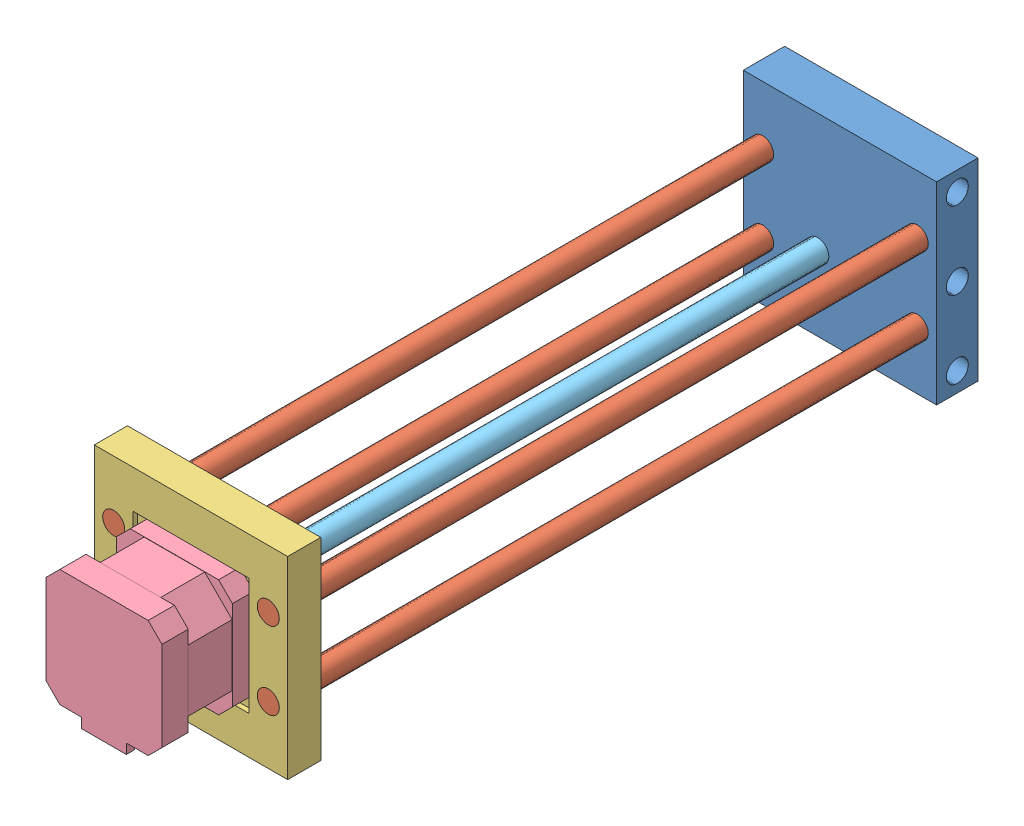
SolidWorks assembly Ensamblaje_Link2.2, configuration Predeterminado. Lengths in mm.
Overall size (70 70 281.5).
8 component instances, 5 part files, 19 mates.
Components (placement in the parent):
- Pieza3-1: Pieza3 [Predeterminado] x (-1 0 0) z (0 1 0) size (70 15 70)
- Pieza2-1: Pieza2 [Predeterminado] at (28 -14 0) x (0 0 1) z (-1 0 0) size (250 8 8)
- Pieza2-2: Pieza2 [Predeterminado] at (28 14 0) x (0 0 1) z (-1 0 0) size (250 8 8)
- Pieza2-3: Pieza2 [Predeterminado] at (-28 14 0) x (0 0 1) z (-1 0 0) size (250 8 8)
- Pieza2-4: Pieza2 [Predeterminado] at (-28 -14 0) x (0 0 1) z (-1 0 0) size (250 8 8)
- Pieza4-1: Pieza4 [Predeterminado] at (0 0 238) x (0 1 0) z (1 0 0) size (70 12 70)
- Motor Paso a Paso-1: Motor Paso a Paso [Predeterminado] at (0 0 281.5) x (-1 0 0) z (0 -1 0) size (42 55.2 46)
- Pieza6-1: Pieza6 [Predeterminado] at (0 0 23) x (1 0 0) z (0 -1 0) size (8 215 8)
Mates (geometry in assembly coordinates):
- Coincidente1: coincident aligned: plane of Pieza3-1 through (0 0 0) normal (0 0 1)
- Coincidente2: coincident aligned: plane of Pieza3-1 through (0 0 0) normal (0 1 0)
- Coincidente3: coincident anti-aligned: plane of Pieza3-1 through (0 0 0) normal (-1 0 0)
- Concéntrica1: concentric anti-aligned: cylinder of Pieza3-1 through (-28 -14 0) axis (0 0 1) radius 4; cylinder of Pieza2-4 through (-28 -14 250) axis (0 0 -1) radius 4
- Coincidente4: coincident aligned: plane of Pieza3-1 through (0 0 0) normal (0 0 -1); plane of Pieza2-4 through (-28 -14 0) normal (0 0 -1)
- Concéntrica2: concentric anti-aligned: cylinder of Pieza3-1 through (-28 14 0) axis (0 0 1) radius 4; cylinder of Pieza2-3 through (-28 14 250) axis (0 0 -1) radius 4
- Coincidente5: coincident aligned: plane of Pieza3-1 through (0 0 0) normal (0 0 -1); plane of Pieza2-3 through (-28 14 0) normal (0 0 -1)
- Concéntrica3: concentric anti-aligned: cylinder of Pieza3-1 through (28 14 0) axis (0 0 1) radius 4; cylinder of Pieza2-2 through (28 14 250) axis (0 0 -1) radius 4
- Coincidente6: coincident aligned: plane of Pieza3-1 through (0 0 0) normal (0 0 -1); plane of Pieza2-2 through (28 14 0) normal (0 0 -1)
- Concéntrica4: concentric anti-aligned: cylinder of Pieza3-1 through (28 -14 0) axis (0 0 1) radius 4; cylinder of Pieza2-1 through (28 -14 250) axis (0 0 -1) radius 4
- Coincidente7: coincident aligned: plane of Pieza3-1 through (0 0 0) normal (0 0 -1); plane of Pieza2-1 through (28 -14 0) normal (0 0 -1)
- Coincidente8: coincident aligned: plane of Pieza2-1 through (28 -14 250) normal (0 0 1); plane of Pieza4-1 through (0 0 250) normal (0 0 1)
- Concéntrica8: concentric anti-aligned: cylinder of Pieza2-4 through (-28 -14 250) axis (0 0 -1) radius 4; cylinder of Pieza4-1 through (-28 -14 238) axis (0 0 1) radius 4
- Concéntrica9: concentric anti-aligned: cylinder of Pieza2-1 through (28 -14 250) axis (0 0 -1) radius 4; cylinder of Pieza4-1 through (28 -14 238) axis (0 0 1) radius 4
- Concéntrica10: concentric aligned: cylinder of Pieza4-1 through (0 0 246.3) axis (0 0 1) radius 11; cylinder of Motor Paso a Paso-1 through (0 0 246.3) axis (0 0 1) radius 11
- Coincidente9: coincident anti-aligned: plane of Pieza4-1 through (21 -21.2 248.3) normal (0 1 0); plane of Motor Paso a Paso-1 through (16 -21.2 248.3) normal (0 -1 0)
- Coincidente10: coincident anti-aligned: plane of Pieza4-1 through (0 0 248.3) normal (0 0 1); plane of Motor Paso a Paso-1 through (0 0 248.3) normal (0 0 -1)
- Concéntrica12: concentric anti-aligned: cylinder of Motor Paso a Paso-1 through (0 0 226.3) axis (0 0 1) radius 2.5; cylinder of Pieza6-1 through (0 0 238) axis (0 0 -1) radius 4
- Coincidente11: coincident anti-aligned: plane of Pieza4-1 through (0 0 238) normal (0 0 -1); plane of Pieza6-1 through (0 0 238) normal (0 0 1)
